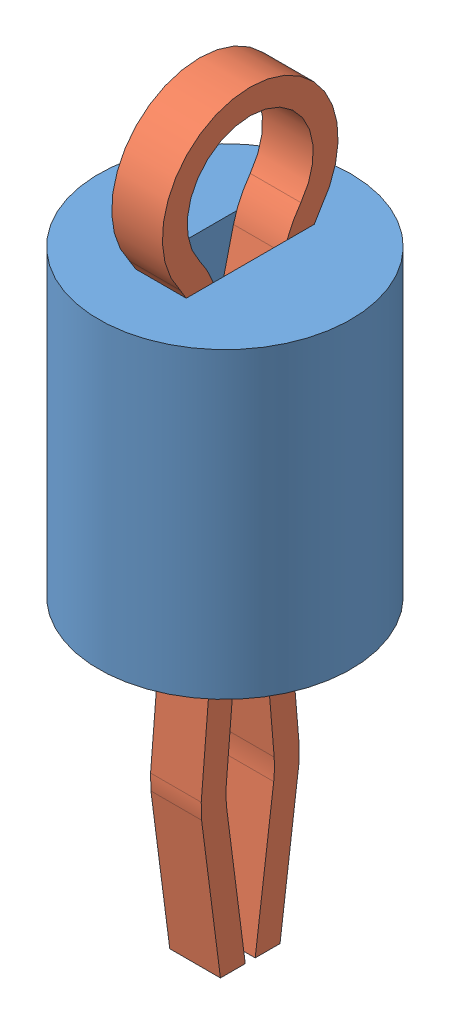
SolidWorks assembly Assem1, configuration Default. Lengths in mm.
Overall size (2.54 7.62 2.54).
2 component instances, 2 part files, 6 mates.
Components (placement in the parent):
- Spacer-brown-1: Spacer-brown [Default] x (0 0 -1) z (0 1 0) size (2.54 2.54 3.05)
- Contact-1: Contact [Default] x (0 0 -1) z (0 1 0) size (1.77 0.51 7.62)
Mates (geometry in assembly coordinates):
- Coincident1: coincident anti-aligned: plane of Spacer-brown-1 through (0 0 0) normal (-1 0 0)
- Coincident2: coincident anti-aligned: plane of Spacer-brown-1 through (0 0 0) normal (0 0 -1)
- Coincident3: coincident anti-aligned: plane of Spacer-brown-1 through (0 0 0) normal (0 -1 0)
- Coincident4: coincident anti-aligned: plane of Contact-1 through (0 0 0) normal (-1 0 0)
- Coincident5: coincident anti-aligned: plane of Contact-1 through (0 0 0) normal (0 0 -1)
- Distance1: distance = 3.05 mm aligned: plane of Spacer-brown-1 through (0 0 0) normal (0 -1 0); plane of Contact-1 through (0 -3.05 0.175) normal (0 -1 0)
